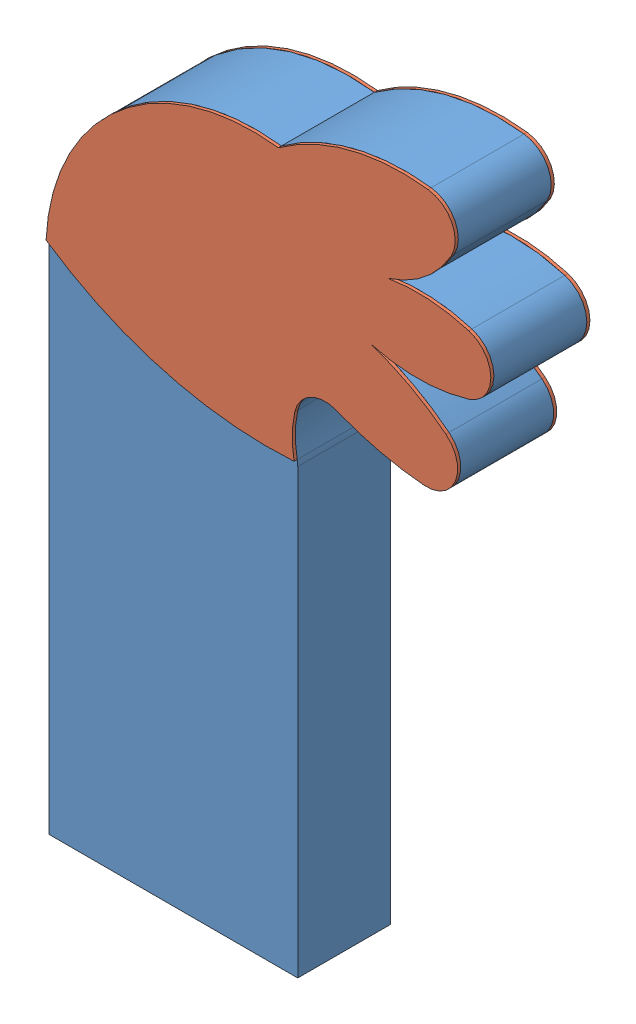
SolidWorks assembly arm_coloured, configuration Predeterminado. Lengths in mm.
Overall size (14.36 24.3 3.2).
3 component instances, 2 part files, 4 mates.
Components (placement in the parent):
- arm-1: arm [Predeterminado] at (-13.537 34.5496 22.8007) size (14.36 24.3 3)
- glove-1: glove [Predeterminado] at (-34.3627 -8.7405 25.8007) size (14.36 9.84 0.1)
- glove-2: glove [Predeterminado] at (-34.3627 -8.7405 22.7007) size (14.36 9.84 0.1)
Mates (geometry in assembly coordinates):
- Coincidente1: coincident: plane of arm-1 through (0.1775 12.9479 25.8007) normal (0 0 1); plane of glove-1 through (-4.8948 10.2427 25.8007) normal (0 0 -1)
- Concéntrica1: concentric: cylinder of arm-1 through (-5.142 4.8109 25.8007) axis (0 0 -1) radius 6.6874; cylinder of glove-1 through (-5.142 4.8109 25.9007) axis (0 0 -1) radius 6.6874
- Coincidente2: coincident: plane of arm-1 through (0.1775 12.9479 22.8007) normal (0 0 -1); plane of glove-2 through (-4.8948 10.2427 22.8007) normal (0 0 1)
- Concéntrica2: concentric: circle of arm-1; circle of glove-2
